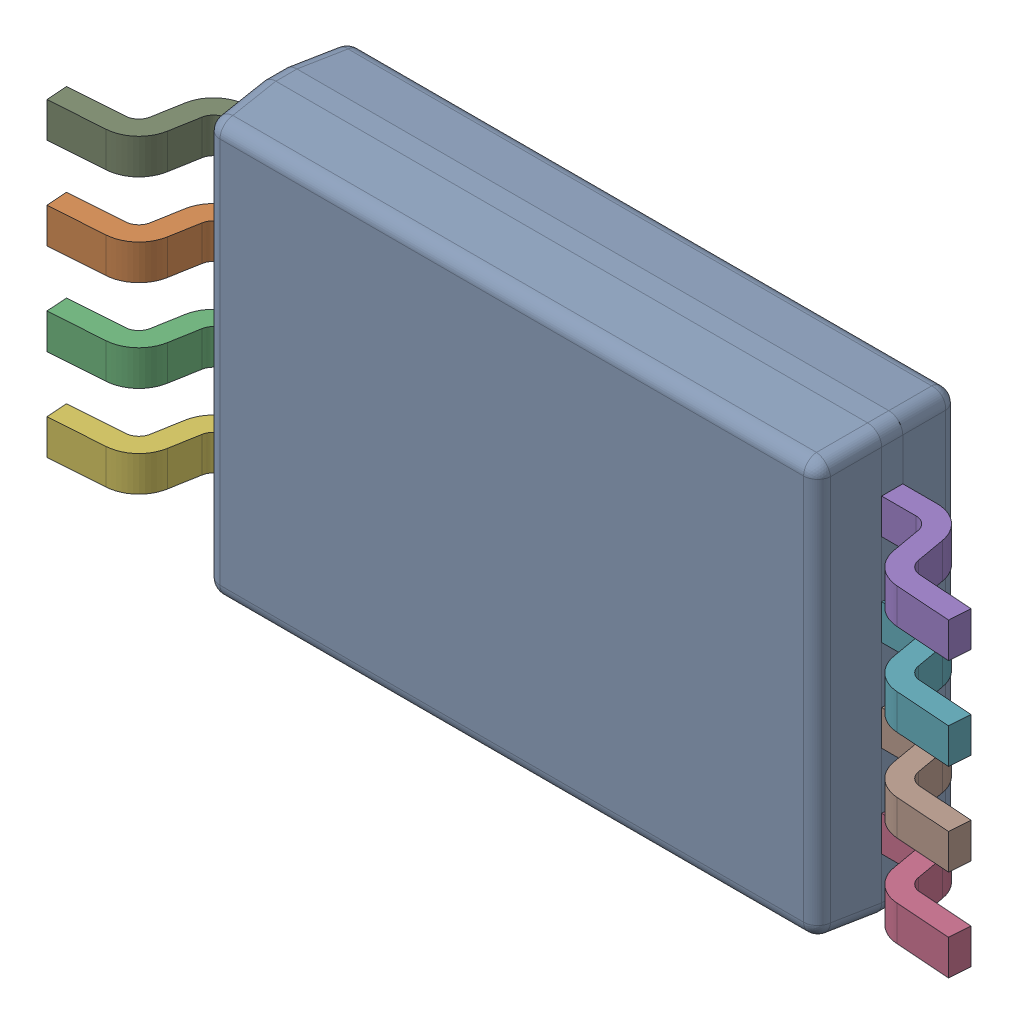
SolidWorks assembly IC5, configuration По умолчанию. Lengths in mm.
Overall size (6.42 3.01 1.1).
10 component instances, 2 part files, 0 mates.
Components (placement in the parent):
- PW0008A_ASM-1: PW0008A_ASM [По умолчанию] at origin size (6.42 3.01 1.1)
  - PW0008A_ASM-Part-1-1: PW0008A_ASM-Part-1 [По умолчанию] at origin size (4.41 3.01 1)
  - PW0008A_ASM-Part-2-1: PW0008A_ASM-Part-2 [По умолчанию] at (-2.575 0.325 -2.3511) x (0 1 0) z (-1 0 0) size (0.25 0.68 1.01)
  - PW0008A_ASM-Part-2-2: PW0008A_ASM-Part-2 [По умолчанию] at (-2.575 -0.325 -2.3511) x (0 1 0) z (-1 0 0) size (0.25 0.68 1.01)
  - PW0008A_ASM-Part-2-3: PW0008A_ASM-Part-2 [По умолчанию] at (2.575 -0.975 -2.3511) x (0 -1 0) z (1 0 0) size (0.25 0.68 1.01)
  - PW0008A_ASM-Part-2-4: PW0008A_ASM-Part-2 [По умолчанию] at (2.575 0.975 -2.3511) x (0 -1 0) z (1 0 0) size (0.25 0.68 1.01)
  - PW0008A_ASM-Part-2-5: PW0008A_ASM-Part-2 [По умолчанию] at (-2.575 -0.975 -2.3511) x (0 1 0) z (-1 0 0) size (0.25 0.68 1.01)
  - PW0008A_ASM-Part-2-6: PW0008A_ASM-Part-2 [По умолчанию] at (2.575 0.325 -2.3511) x (0 -1 0) z (1 0 0) size (0.25 0.68 1.01)
  - PW0008A_ASM-Part-2-7: PW0008A_ASM-Part-2 [По умолчанию] at (2.575 -0.325 -2.3511) x (0 -1 0) z (1 0 0) size (0.25 0.68 1.01)
  - PW0008A_ASM-Part-2-8: PW0008A_ASM-Part-2 [По умолчанию] at (-2.575 0.975 -2.3511) x (0 1 0) z (-1 0 0) size (0.25 0.68 1.01)
